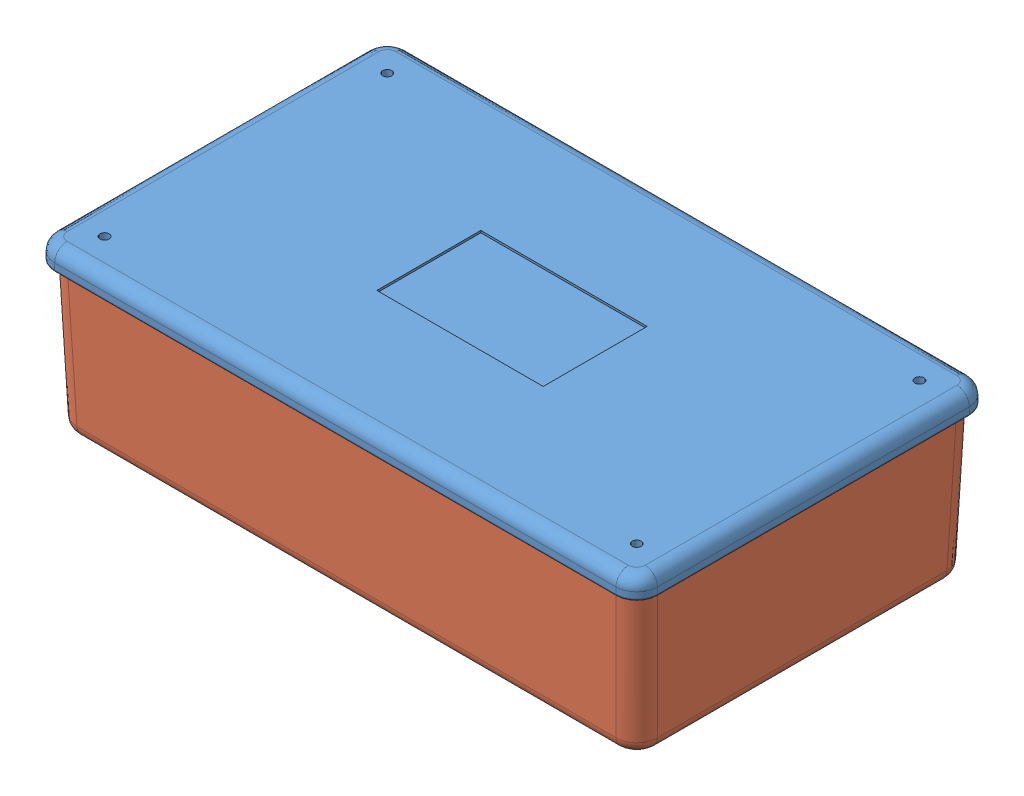
SolidWorks assembly Project Box, configuration Default. Lengths in mm.
Overall size (145 40 85).
203 component instances, 33 part files, 12 mates.
Components (placement in the parent):
- Box bottom-1: Box bottom [Default] at origin size (145 10 85)
- Box top-1: Box top [Default] at (0 2 0) x (-1 0 0) z (0 0 1) size (141.86 37 81.86)
- Box PCB-1: Box PCB [Default] at origin size (128 1.7 70) (hidden)
- controleo3_clone-1: controleo3_clone [Default] at (-64 -25.3882 35) x (1 0 0) z (0 1 0) size (128 72.88 15.5)
  - controleo3_clone.step-1: controleo3_clone.step [Default] at origin size (128 72.88 15.5)
    - Board.step-1: Board.step [Default] at origin size (128 70 1.61)
      - Open CASCADE STEP translator 6.8 1.1.1.step-1: Open CASCADE STEP translator 6.8 1.1.1.step [Default] at (0 0 -1.6118) size (128 70 1.61)
    - R34.step-1: R34.step [Default] at origin size (0.8 1.6 0.45)
      - RES_0603.step-1: RES_0603.step [Default] at (59.14 41.5101 0) x (0 1 0) z (1 0 0) size (1.6 0.45 0.8)
    - R33.step-1: R33.step [Default] at origin size (1.6 0.8 0.45)
      - RES_0603.step-1: RES_0603.step [Default] at (57.4401 35.63 0) x (1 0 0) z (0 -1 0) size (1.6 0.45 0.8)
    - R32.step-1: R32.step [Default] at origin size (0.8 1.6 0.45)
      - RES_0603.step-1: RES_0603.step [Default] at (57.51 41.5401 0) x (0 1 0) z (1 0 0) size (1.6 0.45 0.8)
    - R31.step-1: R31.step [Default] at origin size (0.8 1.6 0.45)
      - RES_0603.step-1: RES_0603.step [Default] at (59.14 38.7401 0) x (0 1 0) z (1 0 0) size (1.6 0.45 0.8)
    - R30.step-1: R30.step [Default] at origin size (0.8 1.6 0.45)
      - RES_0603.step-1: RES_0603.step [Default] at (57.85 50.0301 0) x (0 1 0) z (1 0 0) size (1.6 0.45 0.8)
    - Q2.step-1: Q2.step [Default] at origin size (3.1 3 1.45)
      - SC-59A.step-1: SC-59A.step [Default] at (56.1851 37.0251 0) x (1 0 0) z (0 0 1) size (3.1 3 1.45)
        - Open CASCADE STEP translator 6.8 1.7.1.1.step-1: Open CASCADE STEP translator 6.8 1.7.1.1.step [Default] at origin size (3.1 3 1.45)
        - Open CASCADE STEP translator 6.8 1.7.1.2.step-1: Open CASCADE STEP translator 6.8 1.7.1.2.step [Default] at origin
    - C23.step-1: C23.step [Default] at origin size (0.8 1.6 0.5)
      - CAPC0603_v1.step-1: CAPC0603_v1.step [Default] at (56.3999 27.6301 0) x (0 1 0) z (0 0 1) size (1.6 0.8 0.5)
    - C22.step-1: C22.step [Default] at origin size (2 1.27 1.27)
      - 0805_cap.step-1: 0805_cap.step [Default] at (50.4801 57.117 0.62) x (-1 0 0) z (0 0 1) size (2 1.27 1.27)
    - C4.step-1: C4.step [Default] at origin size (1.6 0.8 0.5)
      - CAPC0603_v1.step-1: CAPC0603_v1.step [Default] at (47.2501 56.4801 0) x (1 0 0) z (0 0 1) size (1.6 0.8 0.5)
    - C7.step-1: C7.step [Default] at origin size (0.8 1.6 0.5)
      - CAPC0603_v1.step-1: CAPC0603_v1.step [Default] at (56.4399 50.0401 0) x (0 1 0) z (0 0 1) size (1.6 0.8 0.5)
    - R29.step-1: R29.step [Default] at origin size (2 1.25 0.6)
      - 0805_resistor.step-1: 0805_resistor.step [Default] at (8.0799 27.775 0) x (-1 0 0) z (0 1 0) size (2 0.6 1.25)
    - R28.step-1: R28.step [Default] at origin size (1.6 0.8 0.45)
      - RES_0603.step-1: RES_0603.step [Default] at (94.0199 19.95 0) x (-1 0 0) z (0 1 0) size (1.6 0.45 0.8)
    - R27.step-1: R27.step [Default] at origin size (0.8 1.6 0.45)
      - RES_0603.step-1: RES_0603.step [Default] at (98.63 59.6599 0) x (0 -1 0) z (-1 0 0) size (1.6 0.45 0.8)
    - R26.step-1: R26.step [Default] at origin size (0.8 1.6 0.45)
      - RES_0603.step-1: RES_0603.step [Default] at (106.27 59.5199 0) x (0 -1 0) z (-1 0 0) size (1.6 0.45 0.8)
    - R25.step-1: R25.step [Default] at origin size (1.6 0.8 0.45)
      - RES_0603.step-1: RES_0603.step [Default] at (94.0699 23.75 0) x (-1 0 0) z (0 1 0) size (1.6 0.45 0.8)
    - R18.step-1: R18.step [Default] at origin size (1.6 0.8 0.45)
      - RES_0603.step-1: RES_0603.step [Default] at (94.2399 27.33 0) x (-1 0 0) z (0 1 0) size (1.6 0.45 0.8)
    - R17.step-1: R17.step [Default] at origin size (1.6 0.8 0.45)
      - RES_0603.step-1: RES_0603.step [Default] at (94.2099 31.05 0) x (-1 0 0) z (0 1 0) size (1.6 0.45 0.8)
    - R16.step-1: R16.step [Default] at origin size (1.6 0.8 0.45)
      - RES_0603.step-1: RES_0603.step [Default] at (94.1799 34.89 0) x (-1 0 0) z (0 1 0) size (1.6 0.45 0.8)
    - P9.step-1: P9.step [Default] at origin size (7.95 7 6.74)
      - JST-B2B-PH-SM4-TB.step-1: JST-B2B-PH-SM4-TB.step [Default] at (14.7349 2.8799 0) x (1 0 0) z (0 -1 0) size (7.95 6.74 7)
    - C12.step-1: C12.step [Default] at origin size (8.3 9.9 10.5)
      - CAP_ALUM_8_3mm.step-1: CAP_ALUM_8_3mm.step [Default] at (54.1901 6.9299 0) x (0 -1 0) z (-1 0 0) size (9.9 10.5 8.3)
    - U2.step-1: U2.step [Default] at origin size (15.1 15.1 1.2)
      - 5887058672.step-1: 5887058672.step [Default] at (74.88 41.62 0) x (0.707107 -0.707107 0) z (0 0 1) size (11.99 11.99 1.2)
    - U1.step-1: U1.step [Default] at origin size (6.7 7.2 1.9)
      - SOT-223-2.step-1: SOT-223-2.step [Default] at (19.1599 36.0099 0.5) x (-1 0 0) z (0 0 1) size (6.7 7.2 1.9)
        - User_Library-SOT-223-2_PIN_SOT-223_2_1.step-1: User_Library-SOT-223-2_PIN_SOT-223_2_1.step [Default] at (-0.7519 -1.8225 0.05) x (0 0 -1) z (1 0 0) size (0.9 1.94 0.7)
        - User_Library-SOT-223-2_SOT-223_1.step-1: User_Library-SOT-223-2_SOT-223_1.step [Default] at (-0.3519 -0.0725 0.05) size (6.7 3.5 1.8)
        - User_Library-SOT-223-2_PIN_SOT-223_2_1.step-2: User_Library-SOT-223-2_PIN_SOT-223_2_1.step [Default] at (-3.0519 -1.8225 0.05) x (0 0 -1) z (1 0 0) size (0.9 1.94 0.7)
        - User_Library-SOT-223-2_PIN_SOT-223_1.step-1: User_Library-SOT-223-2_PIN_SOT-223_1.step [Default] at (1.1481 1.6775 0.05) x (0 0 -1) z (-1 0 0) size (0.9 1.94 3)
        - User_Library-SOT-223-2_PIN_SOT-223_2_1.step-3: User_Library-SOT-223-2_PIN_SOT-223_2_1.step [Default] at (1.5481 -1.8225 0.05) x (0 0 -1) z (1 0 0) size (0.9 1.94 0.7)
    - SD1.step-1: SD1.step [Default] at origin size (14.75 14.5 2.65)
      - SD-Card_socket.step-1: SD-Card_socket.step [Default] at (63.6949 65.6349 0) x (-1 0 0) z (0 1 0) size (14.75 2.65 14.5)
    - R24.step-1: R24.step [Default] at origin size (1.6 0.8 0.45)
      - RES_0603.step-1: RES_0603.step [Default] at (116.5899 53 0) x (-1 0 0) z (0 1 0) size (1.6 0.45 0.8)
    - R23.step-1: R23.step [Default] at origin size (1.6 0.8 0.45)
      - RES_0603.step-1: RES_0603.step [Default] at (116.6299 48.03 0) x (-1 0 0) z (0 1 0) size (1.6 0.45 0.8)
    - R22.step-1: R22.step [Default] at origin size (1.6 0.8 0.45)
      - RES_0603.step-1: RES_0603.step [Default] at (40.0901 12.99 0) x (1 0 0) z (0 -1 0) size (1.6 0.45 0.8)
    - R21.step-1: R21.step [Default] at origin size (1.6 0.8 0.45)
      - RES_0603.step-1: RES_0603.step [Default] at (43.2701 12.97 0) x (1 0 0) z (0 -1 0) size (1.6 0.45 0.8)
    - R20.step-1: R20.step [Default] at origin size (0.8 1.6 0.45)
      - RES_0603.step-1: RES_0603.step [Default] at (96.61 19.7201 0) x (0 1 0) z (1 0 0) size (1.6 0.45 0.8)
    - R19.step-1: R19.step [Default] at origin size (2 1.25 0.6)
      - 0805_resistor.step-1: 0805_resistor.step [Default] at (105.0601 20.245 0) x (1 0 0) z (0 -1 0) size (2 0.6 1.25)
    - R15.step-1: R15.step [Default] at origin size (0.8 1.6 0.45)
      - RES_0603.step-1: RES_0603.step [Default] at (96.5899 23.4101 0) x (0 1 0) z (1 0 0) size (1.6 0.45 0.8)
    - R14.step-1: R14.step [Default] at origin size (0.8 1.6 0.45)
      - RES_0603.step-1: RES_0603.step [Default] at (56.7 41.5199 0) x (0 -1 0) z (-1 0 0) size (1.6 0.45 0.8)
    - R13.step-1: R13.step [Default] at origin size (2 1.25 0.6)
      - 0805_resistor.step-1: 0805_resistor.step [Default] at (105.0401 23.935 0) x (1 0 0) z (0 -1 0) size (2 0.6 1.25)
    - R12.step-1: R12.step [Default] at origin size (1.25 2 0.6)
      - 0805_resistor.step-1: 0805_resistor.step [Default] at (60.695 4.1199 0) x (0 -1 0) z (-1 0 0) size (2 0.6 1.25)
    - R11.step-1: R11.step [Default] at origin size (0.8 1.6 0.45)
      - RES_0603.step-1: RES_0603.step [Default] at (96.6199 27.1301 0) x (0 1 0) z (1 0 0) size (1.6 0.45 0.8)
    - R10.step-1: R10.step [Default] at origin size (0.8 1.6 0.45)
      - RES_0603.step-1: RES_0603.step [Default] at (81.57 52.3399 0) x (0 -1 0) z (-1 0 0) size (1.6 0.45 0.8)
    - R9.step-1: R9.step [Default] at origin size (2 1.25 0.6)
      - 0805_resistor.step-1: 0805_resistor.step [Default] at (104.9701 27.655 0) x (1 0 0) z (0 -1 0) size (2 0.6 1.25)
    - R8.step-1: R8.step [Default] at origin size (0.8 1.6 0.45)
      - RES_0603.step-1: RES_0603.step [Default] at (96.65 30.8401 0) x (0 1 0) z (1 0 0) size (1.6 0.45 0.8)
    - R7.step-1: R7.step [Default] at origin size (2 1.25 0.6)
      - 0805_resistor.step-1: 0805_resistor.step [Default] at (105.0001 31.385 0) x (1 0 0) z (0 -1 0) size (2 0.6 1.25)
    - R6.step-1: R6.step [Default] at origin size (0.8 1.6 0.45)
      - RES_0603.step-1: RES_0603.step [Default] at (96.64 34.5801 0) x (0 1 0) z (1 0 0) size (1.6 0.45 0.8)
    - R5.step-1: R5.step [Default] at origin size (2 1.25 0.6)
      - 0805_resistor.step-1: 0805_resistor.step [Default] at (105.0401 35.155 0) x (1 0 0) z (0 -1 0) size (2 0.6 1.25)
    - R4.step-1: R4.step [Default] at origin size (1.6 0.8 0.45)
      - RES_0603.step-1: RES_0603.step [Default] at (88.7101 62.44 0) x (1 0 0) z (0 -1 0) size (1.6 0.45 0.8)
    - R3.step-1: R3.step [Default] at origin size (1.6 0.8 0.45)
      - RES_0603.step-1: RES_0603.step [Default] at (88.7401 64.09 0) x (1 0 0) z (0 -1 0) size (1.6 0.45 0.8)
    - R2.step-1: R2.step [Default] at origin size (1.6 0.8 0.45)
      - RES_0603.step-1: RES_0603.step [Default] at (80.6399 62.22 0) x (-1 0 0) z (0 1 0) size (1.6 0.45 0.8)
    - R1.step-1: R1.step [Default] at origin size (1.25 2 0.6)
      - 0805_resistor.step-1: 0805_resistor.step [Default] at (92.695 64.3101 0) x (0 1 0) z (1 0 0) size (2 0.6 1.25)
    - Q5.step-1: Q5.step [Default] at origin size (4.5 5.1 1.1)
      - 5908523488.step-1: 5908523488.step [Default] at (108.1 51.34 0.1) size (4.5 5.1 1.1)
        - Extruded.step-1: Extruded.step [Default] at origin size (4.5 5.1 1.1)
    - Q4.step-1: Q4.step [Default] at origin size (6.41 5 2.14)
      - SOIC08_narrow.step-1: SOIC08_narrow.step [Default] at (74.7801 26.5201 0) x (0 1 0) z (0 0 1) size (5 6.41 2.14)
    - Q3.step-1: Q3.step [Default] at origin size (3.1 3 1.45)
      - SC-59A.step-1: SC-59A.step [Default] at (40.9849 10.6549 0) x (-1 0 0) z (0 0 1) size (3.1 3 1.45)
        - Open CASCADE STEP translator 6.8 1.7.1.1.step-1: Open CASCADE STEP translator 6.8 1.7.1.1.step [Default] at origin size (3.1 3 1.45)
        - Open CASCADE STEP translator 6.8 1.7.1.2.step-1: Open CASCADE STEP translator 6.8 1.7.1.2.step [Default] at origin
    - Q1.step-1: Q1.step [Default] at origin size (4.5 5.1 1)
      - 5908523328.step-1: 5908523328.step [Default] at (51.51 52.55 0.1) size (4.5 5.1 1)
        - Extruded-0.step-1: Extruded-0.step [Default] at origin size (4.5 5.1 1)
    - P8.step-1: P8.step [Default] at origin size (9 10 15.5)
      - 237-102.step-1: 237-102.step [Default] at (122.7551 45.9501 0) x (-1 0 0) z (0 1 0) size (9 15.5 10)
    - P5.step-1: P5.step [Default] at origin size (5.11 25.43 2.06)
      - c-4-1734839-0-c-3d.step-1: c-4-1734839-0-c-3d.step [Default] at (48.85 35.0101 1) x (0 -1 0) z (-1 0 0) size (25.43 2.06 5.11)
    - P4.step-1: P4.step [Default] at origin size (9 15 15.5)
      - 237-103.step-1: 237-103.step [Default] at (122.7601 13.4951 0) x (-1 0 0) z (0 1 0) size (9 15.5 15)
    - P2.step-1: P2.step [Default] at origin size (9 15 15.5)
      - 237-103.step-1: 237-103.step [Default] at (122.7701 28.4951 0) x (-1 0 0) z (0 1 0) size (9 15.5 15)
    - P1.step-1: P1.step [Default] at origin size (9 10 15.5)
      - 237-102.step-1: 237-102.step [Default] at (5.3249 42.2799 0) x (1 0 0) z (0 -1 0) size (9 15.5 10)
    - NF5.step-1: NF5.step [Default] at origin size (3 3.1 1.45)
      - SC-59A.step-1: SC-59A.step [Default] at (98.9851 20.5449 0) x (0 -1 0) z (0 0 1) size (3.1 3 1.45)
        - Open CASCADE STEP translator 6.8 1.7.1.1.step-1: Open CASCADE STEP translator 6.8 1.7.1.1.step [Default] at origin size (3.1 3 1.45)
        - Open CASCADE STEP translator 6.8 1.7.1.2.step-1: Open CASCADE STEP translator 6.8 1.7.1.2.step [Default] at origin
    - NF4.step-1: NF4.step [Default] at origin size (3 3.1 1.45)
      - SC-59A.step-1: SC-59A.step [Default] at (98.9651 24.2349 0) x (0 -1 0) z (0 0 1) size (3.1 3 1.45)
        - Open CASCADE STEP translator 6.8 1.7.1.1.step-1: Open CASCADE STEP translator 6.8 1.7.1.1.step [Default] at origin size (3.1 3 1.45)
        - Open CASCADE STEP translator 6.8 1.7.1.2.step-1: Open CASCADE STEP translator 6.8 1.7.1.2.step [Default] at origin
    - NF3.step-1: NF3.step [Default] at origin size (3 3.1 1.45)
      - SC-59A.step-1: SC-59A.step [Default] at (98.9951 27.9549 0) x (0 -1 0) z (0 0 1) size (3.1 3 1.45)
        - Open CASCADE STEP translator 6.8 1.7.1.1.step-1: Open CASCADE STEP translator 6.8 1.7.1.1.step [Default] at origin size (3.1 3 1.45)
        - Open CASCADE STEP translator 6.8 1.7.1.2.step-1: Open CASCADE STEP translator 6.8 1.7.1.2.step [Default] at origin
    - NF2.step-1: NF2.step [Default] at origin size (3 3.1 1.45)
      - SC-59A.step-1: SC-59A.step [Default] at (99.0251 31.6849 0) x (0 -1 0) z (0 0 1) size (3.1 3 1.45)
        - Open CASCADE STEP translator 6.8 1.7.1.1.step-1: Open CASCADE STEP translator 6.8 1.7.1.1.step [Default] at origin size (3.1 3 1.45)
        - Open CASCADE STEP translator 6.8 1.7.1.2.step-1: Open CASCADE STEP translator 6.8 1.7.1.2.step [Default] at origin
    - NF1.step-1: NF1.step [Default] at origin size (3 3.1 1.45)
      - SC-59A.step-1: SC-59A.step [Default] at (99.0651 35.4549 0) x (0 -1 0) z (0 0 1) size (3.1 3 1.45)
        - Open CASCADE STEP translator 6.8 1.7.1.1.step-1: Open CASCADE STEP translator 6.8 1.7.1.1.step [Default] at origin size (3.1 3 1.45)
        - Open CASCADE STEP translator 6.8 1.7.1.2.step-1: Open CASCADE STEP translator 6.8 1.7.1.2.step [Default] at origin
    - FB1.step-1: FB1.step [Default] at origin size (1.7 1.7 0.45)
      - 0603_resistor.step-1: 0603_resistor.step [Default] at (67.5629 50.4872 0) x (-0.707107 -0.707107 0) z (-0.707107 0.707107 0) size (1.6 0.45 0.8)
    - D6.step-1: D6.step [Default] at origin size (0.81 1.61 0.4)
      - LED_Blue_SMD_0603_W_rth_150060BS55040.step-1: LED_Blue_SMD_0603_W_rth_150060BS55040.step [Default] at (91.0101 61.37 0) x (0 -1 0) z (0 0 1) size (1.6 0.81 0.4)
    - D5.step-1: D5.step [Default] at origin size (0.81 1.61 0.4)
      - LED_Red_SMD_0603_W_rth_150060SS55040.step-1: LED_Red_SMD_0603_W_rth_150060SS55040.step [Default] at (91.0199 64.34 0) x (0 1 0) z (0 0 1) size (1.6 0.81 0.4)
    - D3.step-1: D3.step [Default] at origin size (2.84 2.93 1.12)
      - sot-23-6.step-1: sot-23-6.step [Default] at (102.0701 60.5099 0.8128) x (0 -1 0) z (-1 0 0) size (2.93 1.12 2.84)
        - BODY_MF06A.step-1: BODY_MF06A.step [Default] at origin size (2.93 1.02 1.61)
        - LEAD_MF06A.step-1: LEAD_MF06A.step [Default] at (0.9525 -0.6604 0.9652) size (0.37 0.86 0.62)
        - LEAD_MF06A.step-2: LEAD_MF06A.step [Default] at (0 -0.6604 0.9652) size (0.37 0.86 0.62)
        - LEAD_MF06A.step-3: LEAD_MF06A.step [Default] at (-0.9525 -0.6604 0.9652) size (0.37 0.86 0.62)
        - LEAD_MF06A.step-4: LEAD_MF06A.step [Default] at (0.9525 -0.6604 -0.9652) x (-1 0 0) z (0 0 -1) size (0.37 0.86 0.62)
        - LEAD_MF06A.step-5: LEAD_MF06A.step [Default] at (0 -0.6604 -0.9652) x (-1 0 0) z (0 0 -1) size (0.37 0.86 0.62)
        - LEAD_MF06A.step-6: LEAD_MF06A.step [Default] at (-0.9525 -0.6604 -0.9652) x (-1 0 0) z (0 0 -1) size (0.37 0.86 0.62)
    - D1.step-1: D1.step [Default] at origin size (1.61 0.81 0.4)
      - LED_Red_SMD_0603_W_rth_150060SS55040.step-1: LED_Red_SMD_0603_W_rth_150060SS55040.step [Default] at (80.64 60.8701 0) x (1 0 0) z (0 0 1) size (1.6 0.81 0.4)
    - C21.step-1: C21.step [Default] at origin size (1.6 0.8 0.5)
      - CAPC0603_v1.step-1: CAPC0603_v1.step [Default] at (106.8301 55.4501 0) x (1 0 0) z (0 0 1) size (1.6 0.8 0.5)
    - C20.step-1: C20.step [Default] at origin size (0.8 1.6 0.5)
      - CAPC0603_v1.step-1: CAPC0603_v1.step [Default] at (113.9901 54.0299 0) x (0 -1 0) z (0 0 1) size (1.6 0.8 0.5)
    - C19.step-1: C19.step [Default] at origin size (1.6 0.8 0.5)
      - CAPC0603_v1.step-1: CAPC0603_v1.step [Default] at (109.9999 55.4399 0) x (-1 0 0) z (0 0 1) size (1.6 0.8 0.5)
    - C18.step-1: C18.step [Default] at origin size (0.8 1.6 0.5)
      - CAPC0603_v1.step-1: CAPC0603_v1.step [Default] at (114.0001 50.9999 0) x (0 -1 0) z (0 0 1) size (1.6 0.8 0.5)
    - C17.step-1: C17.step [Default] at origin size (0.8 1.6 0.5)
      - CAPC0603_v1.step-1: CAPC0603_v1.step [Default] at (114.0001 47.8199 0) x (0 -1 0) z (0 0 1) size (1.6 0.8 0.5)
    - C16.step-1: C16.step [Default] at origin size (0.8 1.6 0.5)
      - CAPC0603_v1.step-1: CAPC0603_v1.step [Default] at (80.4199 29.1701 0) x (0 1 0) z (0 0 1) size (1.6 0.8 0.5)
    - C15.step-1: C15.step [Default] at origin size (1.7 1.7 0.5)
      - CAPC0603_v1.step-1: CAPC0603_v1.step [Default] at (78.1999 32.76 0) x (-0.707107 0.707107 0) z (0 0 1) size (1.6 0.8 0.5)
    - C14.step-1: C14.step [Default] at origin size (1.6 0.8 0.5)
      - CAPC0603_v1.step-1: CAPC0603_v1.step [Default] at (65.8101 37.1701 0) x (1 0 0) z (0 0 1) size (1.6 0.8 0.5)
    - C13.step-1: C13.step [Default] at origin size (1.7 1.7 0.5)
      - CAPC0603_v1.step-1: CAPC0603_v1.step [Default] at (84.58 41.2199 0) x (-0.707107 -0.707107 0) z (0 0 1) size (1.6 0.8 0.5)
    - C11.step-1: C11.step [Default] at origin size (0.8 1.6 0.5)
      - CAPC0603_v1.step-1: CAPC0603_v1.step [Default] at (82.2699 49.5001 0) x (0 1 0) z (0 0 1) size (1.6 0.8 0.5)
    - C10.step-1: C10.step [Default] at origin size (1.7 1.7 0.5)
      - CAPC0603_v1.step-1: CAPC0603_v1.step [Default] at (68.48 49.5499 0) x (-0.707107 -0.707107 0) z (0 0 1) size (1.6 0.8 0.5)
    - C9.step-1: C9.step [Default] at origin size (1.7 1.7 0.5)
      - CAPC0603_v1.step-1: CAPC0603_v1.step [Default] at (69.68 48.3299 0) x (-0.707107 -0.707107 0) z (0 0 1) size (1.6 0.8 0.5)
    - C8.step-1: C8.step [Default] at origin size (0.8 1.6 0.5)
      - CAPC0603_v1.step-1: CAPC0603_v1.step [Default] at (80.6799 49.4901 0) x (0 1 0) z (0 0 1) size (1.6 0.8 0.5)
    - C6.step-1: C6.step [Default] at origin size (1.6 0.8 0.5)
      - CAPC0603_v1.step-1: CAPC0603_v1.step [Default] at (72.8999 50.6199 0) x (-1 0 0) z (0 0 1) size (1.6 0.8 0.5)
    - C5.step-1: C5.step [Default] at origin size (1.6 0.8 0.5)
      - CAPC0603_v1.step-1: CAPC0603_v1.step [Default] at (76.6901 50.6101 0) x (1 0 0) z (0 0 1) size (1.6 0.8 0.5)
    - C3.step-1: C3.step [Default] at origin size (3.2 2.5 2.5)
      - CAP_1210-2.5mm.step-1: CAP_1210-2.5mm.step [Default] at (21.0099 43.5101 0) x (-1 0 0) z (0 1 0) size (3.2 2.5 2.5)
    - C2.step-1: C2.step [Default] at origin size (1.27 2 1.27)
      - 0805_cap.step-1: 0805_cap.step [Default] at (16.193 43.4101 0.62) x (0 -1 0) z (0 0 1) size (2 1.27 1.27)
    - C1.step-1: C1.step [Default] at origin size (1.27 2 1.27)
      - 0805_cap.step-1: 0805_cap.step [Default] at (96.207 64.2599 0.62) x (0 1 0) z (0 0 1) size (2 1.27 1.27)
    - B1.step-1: B1.step [Default] at origin size (12 12 12.1)
      - HCM1206X.step-1: HCM1206X.step [Default] at (31.1449 8.5099 0) x (-1 0 0) z (0 0 1) size (12 12 12.1)
    - Free-Models.step-1: Free-Models.step [Default] at origin size (8.95 8.1 3.76)
      - c-2345986-1-1-3d.step-1: c-2345986-1-1-3d.step [Default] at (102.07 71.82 1.6) x (-1 0 0) z (0 1 0) size (8.95 3.76 8.1)
- 4inch LCD-1: 4inch LCD [Default] at (-3 -31 0) x (-1 0 0) z (0 0 1) size (94.5 3.5 61)
- Bezel-1: Bezel [Default] at origin size (126 0.3 66)
Mates (geometry in assembly coordinates):
- Coincident1: coordinate: point of Box bottom-1
- Coincident2: coincident anti-aligned: plane of Box top-1 through (0 2 0) normal (-1 0 0)
- Coincident3: coincident aligned: plane of Box top-1 through (0 2 0) normal (0 0 1)
- Coincident4: coincident anti-aligned: plane of Box bottom-1 through (-64 -5 34) normal (0 -1 0); plane of Box top-1 through (-64 -5 34) normal (0 1 0)
- Coincident5: coordinate: unknown of Part3^Project Box-1
- Coincident6: coincident anti-aligned: plane of Box top-1 through (-60 -27 -25) normal (0 1 0); plane of controleo3_clone-1/controleo3_clone.step-1/Board.step-1/Open CASCADE STEP translator 6.8 1.1.1.step-1 through (-56 -27 35) normal (0 -1 0)
- Concentric1: concentric anti-aligned: cylinder of Box top-1 through (60 -27 -25) axis (0 1 0) radius 1.1; cylinder of controleo3_clone-1/controleo3_clone.step-1/Board.step-1/Open CASCADE STEP translator 6.8 1.1.1.step-1 through (60 -27 -25) axis (0 -1 0) radius 1.4
- Concentric2: concentric anti-aligned: cylinder of Box top-1 through (-60 -27 25) axis (0 1 0) radius 1.1; cylinder of controleo3_clone-1/controleo3_clone.step-1/Board.step-1/Open CASCADE STEP translator 6.8 1.1.1.step-1 through (-60 -27 25) axis (0 -1 0) radius 1.4
- Coincident7: coincident aligned: plane of 4inch LCD-1 through (0 -31 0) normal (1 0 0)
- Coincident8: coincident aligned: plane of 4inch LCD-1 through (-3 -31 0) normal (0 0 1)
- Coincident9: coincident aligned: plane of Box top-1 through (0 -34.5 0) normal (0 -1 0); plane of 4inch LCD-1 through (-3 -34.5 0) normal (0 -1 0)
- Coincident11: coordinate: unknown of Bezel-1
